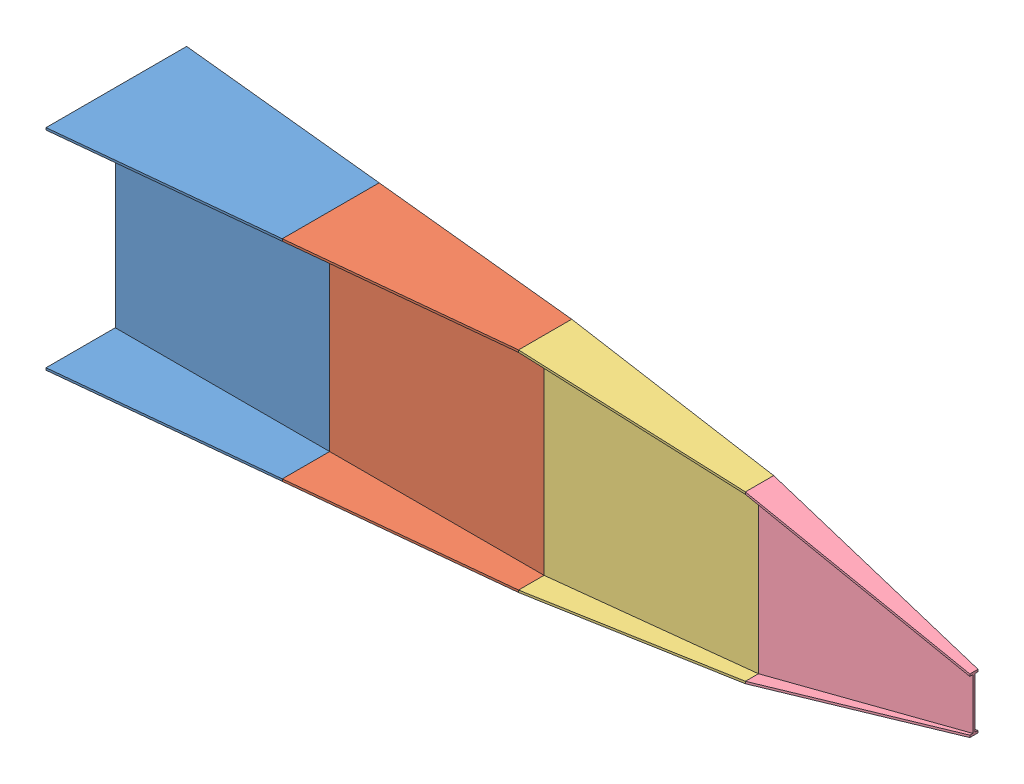
SolidWorks assembly 2.00 tolerance assembly, configuration Default. Lengths in mm.
Overall size (4000 980 656).
4 component instances, 4 part files, 9 mates.
Components (placement in the parent):
- 1-1: 1 [Default] at (-775.9263 612.0858 1043.8579) size (1000 980 656)
- 2-2: 2 [Default] at (224.0737 612.0858 1043.8579) size (1000 980 452)
- 3-2: 3 [Default] at (1224.0737 612.0858 1043.8579) size (1000 980 248)
- 4-2: 4 [Default] at (2224.0737 612.0858 1043.8579) size (1000 775 132)
Mates (geometry in assembly coordinates):
- Coincident39: coincident anti-aligned: plane of 1-1 through (224.0737 612.0858 1043.8579) normal (1 0 0); plane of 2-2 through (224.0737 612.0858 1043.8579) normal (-1 0 0)
- Coincident40: coincident anti-aligned: plane of 2-2 through (1224.0737 612.0858 1043.8579) normal (1 0 0); plane of 3-2 through (1224.0737 612.0858 1043.8579) normal (-1 0 0)
- Coincident42: coincident: point of 1-1; point of 2-2
- Coincident43: coincident: point of 1-1; point of 2-2
- Coincident44: coincident: point of 2-2; point of 3-2
- Coincident46: coincident: point of 2-2; point of 3-2
- Coincident49: coincident: point of 3-2; point of 4-2
- Coincident52: coincident aligned: plane of 3-2 through (1224.0737 612.0858 1053.8579) normal (0 0 1); plane of 4-2 through (2224.0737 612.0858 1053.8579) normal (0 0 1)
- Coincident53: coincident: point of 3-2; point of 4-2
